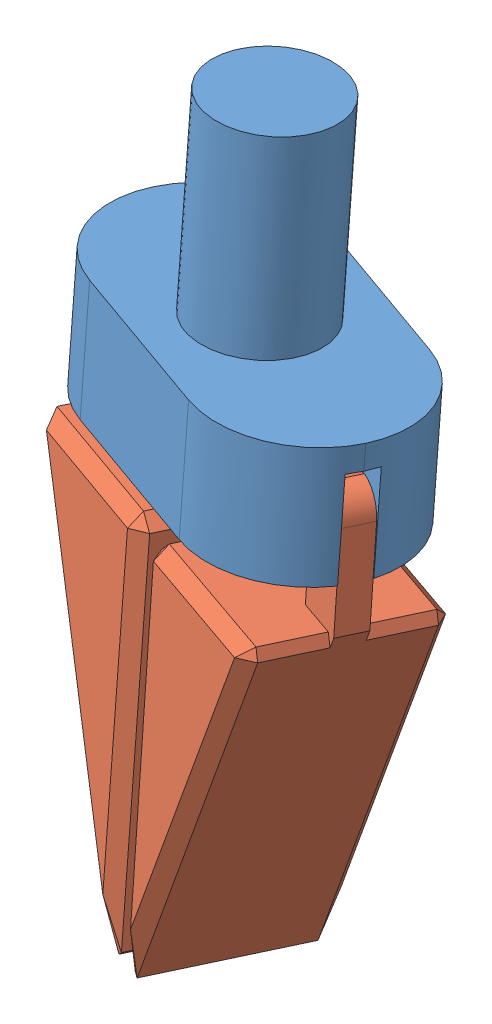
SolidWorks assembly Assem3, configuration Default. Lengths in mm.
Overall size (175.34 311.68 208.02).
3 component instances, 2 part files, 4 mates.
Components (placement in the parent):
- Right End Effector-1: Right End Effector [Default] at (18.3378 147.425 127.4141) x (0.94014 0.011959 0.340578) z (-0.340578 0.068041 0.937751) size (150 130 80)
- Gripper Claw-5: Gripper Claw [Default] at (54.9729 126.0272 104.9487) x (0.940213 0.022035 0.339874) z (-0.002462 -0.997439 0.071478) size (70 70 206.48)
- Gripper Claw-6: Gripper Claw [Default] at (-18.455 130.5449 152.5996) x (-0.940142 -0.012131 -0.340567) z (-0.011797 -0.997609 0.0681) size (70 70 206.48)
Mates (geometry in assembly coordinates):
- Concentric7: concentric anti-aligned: cylinder of Right End Effector-1 through (73.201 161.2504 163.3986) axis (0.340578 -0.068041 -0.937751) radius 7.5; cylinder of Gripper Claw-5 through (83.759 159.1411 134.3284) axis (-0.340578 0.068041 0.937751) radius 7.5
- Width5: width anti-aligned: plane of Right End Effector-1 through (87.2832 188.6346 155.8623) normal (0.340578 -0.068041 -0.937751); plane of Gripper Claw-5 through (91.3701 187.8181 144.6093) normal (-0.340578 0.068041 0.937751); plane of Right End Effector-1 through (41.0092 128.8169 143.3965) normal (-0.340578 0.068041 0.937751); plane of Gripper Claw-5 through (45.0962 128.0004 132.1435) normal (0.340578 -0.068041 -0.937751)
- Concentric10: concentric anti-aligned: cylinder of Right End Effector-1 through (-36.2384 157.5423 89.7966) axis (-0.340578 0.068041 0.937751) radius 7.5; cylinder of Gripper Claw-6 through (-46.7963 159.6516 118.8669) axis (0.340578 -0.068041 -0.937751) radius 7.5
- Width7: width anti-aligned: plane of Right End Effector-1 through (-49.6509 186.0243 93.5226) normal (-0.340578 0.068041 0.937751); plane of Gripper Claw-6 through (-53.7378 186.8408 104.7756) normal (0.340578 -0.068041 -0.937751); plane of Right End Effector-1 through (-4.4913 127.7552 114.1518) normal (0.340578 -0.068041 -0.937751); plane of Gripper Claw-6 through (-8.5783 128.5716 125.4048) normal (-0.340578 0.068041 0.937751)
